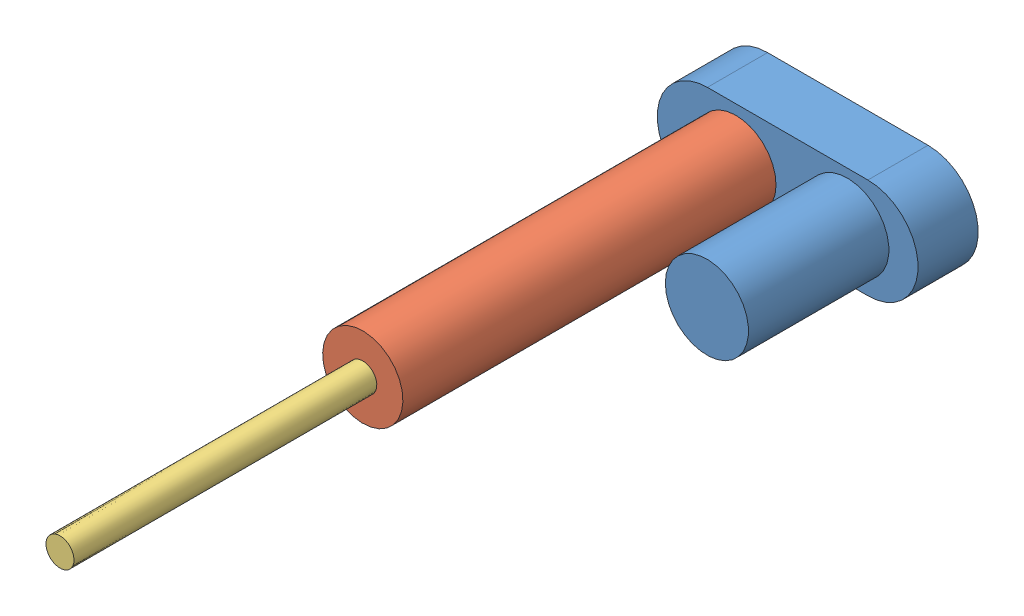
SolidWorks assembly Assem3, configuration Default. Lengths in mm.
Overall size (65 28.2 183.48).
3 component instances, 3 part files, 3 mates.
Components (placement in the parent):
- asnp1-1: asnp1 [Default] at (13.3315 50.9692 44.0787) size (65 25 50)
- np5-1: np5 [Default] at (0.4295 50.9692 54.0787) x (-0.64993 -0.759994 0) z (0 0 1) size (20 20 98)
- np6-1: np6 [Default] at (0.4295 50.9692 227.5598) x (-0.809988 -0.586446 0) z (0 0 -1) size (15 15 120)
Mates (geometry in assembly coordinates):
- LimitDistance1: limit distance = 19.5189 mm anti-aligned: plane of np6-1 through (0.4295 50.9692 127.5598) normal (0 0 1); plane of np5-1 through (0.4295 50.9692 147.0787) normal (0 0 -1)
- Concentric5: concentric aligned: cylinder of np5-1 through (0.4295 50.9692 147.0787) axis (0 0 1) radius 3.5; cylinder of np6-1 through (0.4295 50.9692 127.5598) axis (0 0 1) radius 3.5
- Coincident14: coincident aligned: circle of asnp1-1; circle of np5-1
